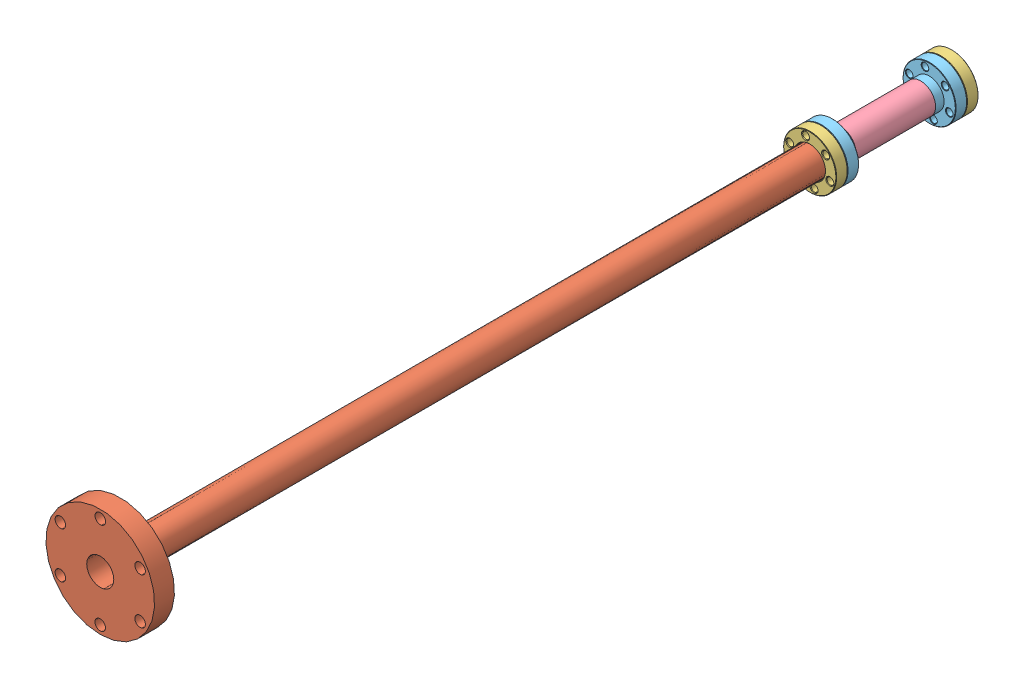
SolidWorks assembly slowertubeassembly, configuration Default. Lengths in mm.
Overall size (69.34 69.34 543.31).
8 component instances, 5 part files, 9 mates.
Components (placement in the parent):
- slower lip GP-3: slower lip GP [Default] at (0 0 209.55) x (0.999854 0.017065 0) z (0 0 1) size (20.57 20.57 3.3)
- slower long tube 09 21 10-1: slower long tube 09 21 10 [Default] at (0 0 294.259) x (1 0 0) z (0 -1 0) size (69.34 457.2 69.34)
- 915000-1: 915000 [Default] at (0 0 215.392) x (0.664273 -0.74749 0) z (0 0 1) size (33.78 33.78 7.24)
- slower bellows-1: slower bellows [Default] at (-11.8613 1.3763 260.2685) x (0.664273 -0.74749 0) z (0.74749 0.664273 0) size (33.78 76.2 33.78)
  - bellows tube-1: bellows tube [Default] at (8.9079 -18.6235 7.9519) size (19.05 50.8 19.05)
  - CF133flange-1: CF133flange [Default] at (8.9079 44.8765 7.9519) x (1 0 0) z (0 1 0) size (33.78 33.78 14.22)
  - CF133flange-2: CF133flange [Default] at (8.9079 -31.3235 7.9519) x (1 0 0) z (0 -1 0) size (33.78 33.78 14.22)
- 915000-2: 915000 [Default] at (0 0 291.592) x (-0.979482 -0.201532 0) z (0 0 -1) size (33.78 33.78 7.24)
Mates (geometry in assembly coordinates):
- Coincident11: coincident anti-aligned: plane of slower lip GP-3 through (0 0 209.55) normal (0 0 -1); plane of 915000-1 through (0 0 209.55) normal (0 0 1)
- Concentric16: concentric anti-aligned: circle of 915000-1; circle of slower bellows-1/CF133flange-1
- Coincident12: coincident anti-aligned: plane of 915000-1 through (0 0 215.392) normal (0 0 1); plane of slower bellows-1/CF133flange-1 through (0 0 215.392) normal (0 0 -1)
- Concentric17: concentric aligned: circle of 915000-1; circle of slower bellows-1/CF133flange-1
- Concentric18: concentric anti-aligned: circle of slower long tube 09 21 10-1; circle of 915000-2
- Coincident13: coincident anti-aligned: plane of slower long tube 09 21 10-1 through (0 0 297.434) normal (0 0 1); plane of 915000-2 through (0 0 297.434) normal (0 0 -1)
- Concentric19: concentric anti-aligned: circle of slower long tube 09 21 10-1; circle of slower bellows-1/CF133flange-2
- Concentric20: concentric anti-aligned: circle of slower bellows-1/CF133flange-2; circle of 915000-2
- Coincident14: coincident anti-aligned: plane of slower bellows-1/CF133flange-2 through (0 0 291.592) normal (0 0 1); plane of 915000-2 through (0 0 291.592) normal (0 0 -1)
